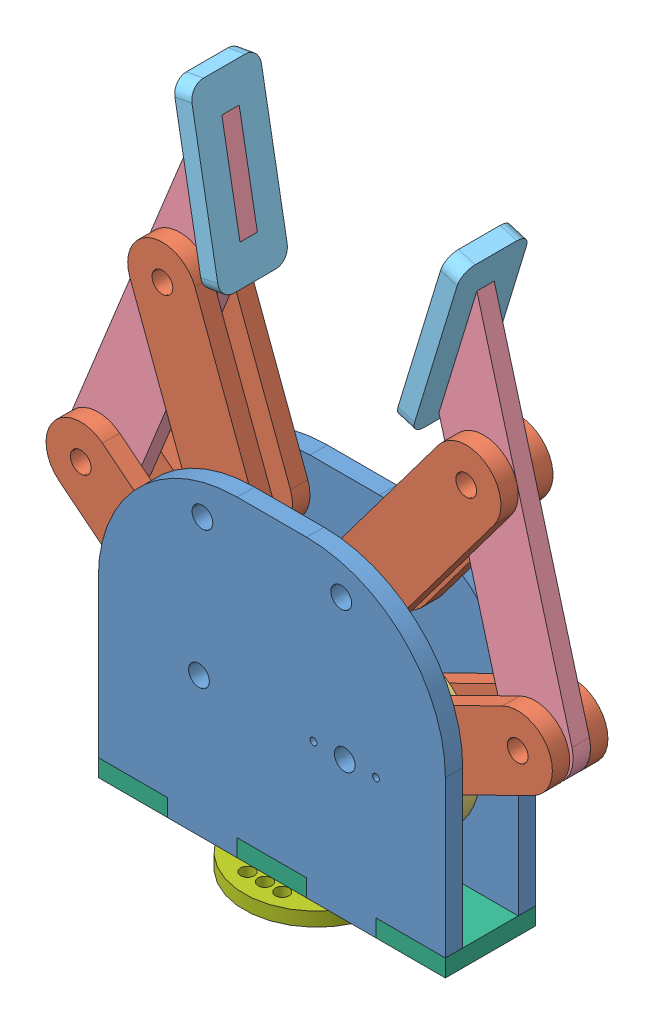
SolidWorks assembly BT_Ensamblaje_PINZA, configuration Predeterminado. Lengths in mm.
Overall size (76.67 96.09 21).
18 component instances, 7 part files, 45 mates.
Components (placement in the parent):
- BT_Base_Pinza-1: BT_Base_Pinza [Predeterminado] at origin size (50 45 2.5)
- BT_Esla_peque-1: BT_Esla_peque [Predeterminado] at (-10.5 -10 8) x (0.62437 0.781129 0) z (0 0 1) size (10 35 2.5)
- BT_Engrane-1: BT_Engrane [Predeterminado] at (-10.5 -10 5) size (23 23 3)
- BT_Engrane-2: BT_Engrane [Predeterminado] at (10.5 -10 5) size (23 23 3)
- BT_Esla_peque-2: BT_Esla_peque [Predeterminado] at (10.5 -10 8) x (0.442571 -0.896734 0) z (0 0 1) size (10 35 2.5)
- BT_Esla_peque-3: BT_Esla_peque [Predeterminado] at (-10.5 -10 2.5) x (0.62437 0.781129 0) z (0 0 1) size (10 35 2.5)
- BT_Esla_peque-4: BT_Esla_peque [Predeterminado] at (10.5 -10 2.5) x (0.442571 -0.896734 0) z (0 0 1) size (10 35 2.5)
- BT_Esla_peque-5: BT_Esla_peque [Predeterminado] at (-10 10 2.5) x (0.936554 0.350522 0) z (0 0 1) size (10 35 2.5)
- BT_Esla_peque-6: BT_Esla_peque [Predeterminado] at (10 10 7.5) x (0.800012 -0.599984 0) z (0 0 1) size (10 35 2.5)
- BT_Esla_peque-7: BT_Esla_peque [Predeterminado] at (-10 10 7.5) x (0.936554 0.350522 0) z (0 0 1) size (10 35 2.5)
- BT_Esla_peque-8: BT_Esla_peque [Predeterminado] at (10 10 2.5) x (0.800012 -0.599984 0) z (0 0 1) size (10 35 2.5)
- BT_Elsa_Grande-1: BT_Elsa_Grande [Predeterminado] at (-30.0282 5.6093 7.5) x (-0.92682 0.375505 0) z (0 0 -1) size (10 58.26 2.5)
- BT_Elsa_Grande-2: BT_Elsa_Grande [Predeterminado] at (32.9183 1.0643 5) x (0.964534 0.263958 0) z (0 0 1) size (10 58.26 2.5)
- BT_Llema-1: BT_Llema [Predeterminado] at (19.489 46.132 6.25) x (0 0 -1) z (0.956576 -0.291484 0) size (10 25 2.5)
- BT_Llema-2: BT_Llema [Predeterminado] at (-11.3944 48.7859 6.25) x (0 0 1) z (-0.984207 -0.177021 0) size (10 25 2.5)
- BT_Base_Pinza-2: BT_Base_Pinza [Predeterminado] at (0 0 10.5) size (50 45 2.5)
- BT_Tapa-1: BT_Tapa [Predeterminado] at (0 -30 6.5) x (1 0 0) z (0 1 0) size (50 13 2.5)
- BT_acople_servos-1: BT_acople_servos [Default] at (0 -31 6.5) x (1 0 0) z (0 -1 0) size (21 21 5.5)
Mates (geometry in assembly coordinates):
- Coincidente1: coincident anti-aligned: plane of BT_Esla_peque-1 through (-30.0282 5.6093 8) normal (0 0 -1); plane of BT_Engrane-1 through (-10.5 -10 8) normal (0 0 1)
- Concéntrica1: concentric aligned: cylinder of BT_Esla_peque-1 through (-10.5 -10 10.5) axis (0 0 -1) radius 1.5; cylinder of BT_Engrane-1 through (-10.5 -10 8) axis (0 0 -1) radius 1.5
- Concéntrica2: concentric aligned: cylinder of BT_Engrane-1 through (-10.5 -10 8) axis (0 0 -1) radius 1.5; cylinder of BT_Esla_peque-3 through (-10.5 -10 5) axis (0 0 -1) radius 1.5
- Coincidente2: coincident anti-aligned: plane of BT_Engrane-1 through (-10.5 -10 5) normal (0 0 -1); plane of BT_Esla_peque-3 through (-30.0282 5.6093 5) normal (0 0 1)
- Concéntrica3: concentric aligned: cylinder of BT_Esla_peque-1 through (-30.0282 5.6093 10.5) axis (0 0 -1) radius 5; cylinder of BT_Esla_peque-3 through (-30.0282 5.6093 5) axis (0 0 -1) radius 5
- Coincidente3: coincident anti-aligned: plane of BT_Engrane-2 through (10.5 -10 8) normal (0 0 1); plane of BT_Esla_peque-2 through (32.9183 1.0643 8) normal (0 0 -1)
- Concéntrica4: concentric aligned: cylinder of BT_Engrane-2 through (10.5 -10 8) axis (0 0 -1) radius 1.5; cylinder of BT_Esla_peque-2 through (10.5 -10 10.5) axis (0 0 -1) radius 1.5
- Coincidente4: coincident anti-aligned: plane of BT_Engrane-2 through (10.5 -10 5) normal (0 0 -1); plane of BT_Esla_peque-4 through (32.9183 1.0643 5) normal (0 0 1)
- Concéntrica5: concentric aligned: cylinder of BT_Engrane-2 through (10.5 -10 8) axis (0 0 -1) radius 1.5; cylinder of BT_Esla_peque-4 through (10.5 -10 5) axis (0 0 -1) radius 1.5
- Concéntrica6: concentric aligned: cylinder of BT_Esla_peque-2 through (32.9183 1.0643 10.5) axis (0 0 -1) radius 5; cylinder of BT_Esla_peque-4 through (32.9183 1.0643 5) axis (0 0 -1) radius 5
- Concéntrica7: concentric aligned: cylinder of BT_Base_Pinza-1 through (10.5 -10 2.5) axis (0 0 -1) radius 1.5; cylinder of BT_Esla_peque-2 through (10.5 -10 10.5) axis (0 0 -1) radius 1.5
- Coincidente5: coincident anti-aligned: plane of BT_Base_Pinza-1 through (5 -5 2.5) normal (0 0 1); plane of BT_Esla_peque-4 through (32.9183 1.0643 2.5) normal (0 0 -1)
- Coincidente6: coincident anti-aligned: plane of BT_Base_Pinza-1 through (5 -5 2.5) normal (0 0 1); plane of BT_Esla_peque-3 through (-30.0282 5.6093 2.5) normal (0 0 -1)
- Concéntrica8: concentric aligned: cylinder of BT_Base_Pinza-1 through (-10.5 -10 2.5) axis (0 0 -1) radius 1.5; cylinder of BT_Esla_peque-1 through (-10.5 -10 10.5) axis (0 0 -1) radius 1.5
- Coincidente7: coincident anti-aligned: circle of BT_Base_Pinza-1; cylinder of BT_Esla_peque-8 through (10 10 5) axis (0 0 -1) radius 1.5
- Concéntrica9: concentric aligned: cylinder of BT_Base_Pinza-1 through (-10 10 2.5) axis (0 0 -1) radius 1.5; cylinder of BT_Esla_peque-5 through (-10 10 5) axis (0 0 -1) radius 1.5
- Coincidente8: coincident anti-aligned: plane of BT_Base_Pinza-1 through (5 -5 2.5) normal (0 0 1); plane of BT_Esla_peque-8 through (24.9996 30.0003 2.5) normal (0 0 -1)
- Coincidente9: coincident anti-aligned: plane of BT_Base_Pinza-1 through (5 -5 2.5) normal (0 0 1); plane of BT_Esla_peque-5 through (-18.7631 33.4139 2.5) normal (0 0 -1)
- Coincidente10: coincident anti-aligned: plane of BT_Esla_peque-3 through (-30.0282 5.6093 5) normal (0 0 1); plane of BT_Elsa_Grande-1 through (-30.0282 5.6093 5) normal (0 0 -1)
- Concéntrica10: concentric anti-aligned: cylinder of BT_Esla_peque-3 through (-30.0282 5.6093 5) axis (0 0 -1) radius 1.5; cylinder of BT_Elsa_Grande-1 through (-30.0282 5.6093 5) axis (0 0 1) radius 1.5
- Concéntrica11: concentric anti-aligned: cylinder of BT_Esla_peque-5 through (-18.7631 33.4139 5) axis (0 0 -1) radius 1.5; cylinder of BT_Elsa_Grande-1 through (-18.7631 33.4139 5) axis (0 0 1) radius 1.5
- Coincidente11: coincident anti-aligned: plane of BT_Esla_peque-4 through (32.9183 1.0643 5) normal (0 0 1); plane of BT_Elsa_Grande-2 through (32.9183 1.0643 5) normal (0 0 -1)
- Concéntrica12: concentric aligned: cylinder of BT_Esla_peque-4 through (32.9183 1.0643 5) axis (0 0 -1) radius 1.5; cylinder of BT_Elsa_Grande-2 through (32.9183 1.0643 7.5) axis (0 0 -1) radius 1.5
- Concéntrica13: concentric aligned: cylinder of BT_Esla_peque-8 through (24.9996 30.0003 5) axis (0 0 -1) radius 1.5; cylinder of BT_Elsa_Grande-2 through (24.9996 30.0003 7.5) axis (0 0 -1) radius 1.5
- Coincidente12: coincident anti-aligned: plane of BT_Elsa_Grande-2 through (19.7267 38.3355 7.5) normal (-0.956576 0.291484 0); plane of BT_Llema-1 through (21.8804 45.4032 6.25) normal (0.956576 -0.291484 0)
- Coincidente13: coincident anti-aligned: plane of BT_Elsa_Grande-2 through (32.9183 1.0643 5) normal (0 0 -1); plane of BT_Llema-1 through (24.0341 52.471 5) normal (0 0 1)
- Coincidente14: coincident anti-aligned: plane of BT_Elsa_Grande-2 through (17.3353 39.0642 7.5) normal (-0.291484 -0.956576 0); plane of BT_Llema-1 through (19.7267 38.3355 7.5) normal (0.291484 0.956576 0)
- Coincidente15: coincident anti-aligned: plane of BT_Elsa_Grande-1 through (-12.547 41.0715 5) normal (0.984207 0.177021 0); plane of BT_Llema-2 through (-13.8549 48.3434 6.25) normal (-0.984207 -0.177021 0)
- Coincidente16: coincident anti-aligned: plane of BT_Elsa_Grande-1 through (-10.0864 41.514 5) normal (0.177021 -0.984207 0); plane of BT_Llema-2 through (-12.547 41.0715 5) normal (-0.177021 0.984207 0)
- Coincidente17: coincident anti-aligned: plane of BT_Elsa_Grande-1 through (-30.0282 5.6093 7.5) normal (0 0 1); plane of BT_Llema-2 through (-15.1628 55.6153 7.5) normal (0 0 -1)
- Concéntrica14: concentric aligned: cylinder of BT_Esla_peque-5 through (-10 10 5) axis (0 0 -1) radius 1.5; cylinder of BT_Esla_peque-7 through (-10 10 10) axis (0 0 -1) radius 1.5
- Coincidente18: coincident anti-aligned: plane of BT_Esla_peque-7 through (-18.7631 33.4139 7.5) normal (0 0 -1); plane of BT_Elsa_Grande-1 through (-30.0282 5.6093 7.5) normal (0 0 1)
- Concéntrica15: concentric anti-aligned: cylinder of BT_Esla_peque-7 through (-18.7631 33.4139 10) axis (0 0 -1) radius 1.5; cylinder of BT_Elsa_Grande-1 through (-18.7631 33.4139 5) axis (0 0 1) radius 1.5
- Coincidente19: coincident anti-aligned: plane of BT_Esla_peque-6 through (24.9996 30.0003 7.5) normal (0 0 -1); plane of BT_Elsa_Grande-2 through (32.9183 1.0643 7.5) normal (0 0 1)
- Concéntrica16: concentric aligned: cylinder of BT_Esla_peque-6 through (10 10 10) axis (0 0 -1) radius 1.5; cylinder of BT_Esla_peque-8 through (10 10 5) axis (0 0 -1) radius 1.5
- Concéntrica17: concentric aligned: cylinder of BT_Esla_peque-6 through (24.9996 30.0003 10) axis (0 0 -1) radius 1.5; cylinder of BT_Elsa_Grande-2 through (24.9996 30.0003 7.5) axis (0 0 -1) radius 1.5
- Coincidente20: coincident anti-aligned: plane of BT_Esla_peque-2 through (32.9183 1.0643 10.5) normal (0 0 1); plane of BT_Base_Pinza-2 through (5 -5 10.5) normal (0 0 -1)
- Coincidente22: coincident aligned: plane of BT_Base_Pinza-1 through (25 -15 2.5) normal (1 0 0); plane of BT_Base_Pinza-2 through (25 -15 13) normal (1 0 0)
- Coincidente23: coincident aligned: plane of BT_Base_Pinza-1 through (-5 -27.5 2.5) normal (0 -1 0); plane of BT_Base_Pinza-2 through (-5 -27.5 13) normal (0 -1 0)
- Coincidente24: coincident anti-aligned: plane of BT_Base_Pinza-2 through (-25 -27.5 13) normal (0 -1 0); plane of BT_Tapa-1 through (0 -27.5 6.5) normal (0 1 0)
- Coincidente25: coincident anti-aligned: plane of BT_Base_Pinza-2 through (5 -5 10.5) normal (0 0 -1); plane of BT_Tapa-1 through (-15 -27.5 10.5) normal (0 0 1)
- Coincidente26: coincident anti-aligned: plane of BT_Base_Pinza-2 through (-15 -27.5 13) normal (-1 0 0); plane of BT_Tapa-1 through (-15 -27.5 13) normal (1 0 0)
- Coincidente27: coincident: plane of BT_Tapa-1 through (0 -30 6.5) normal (0 -1 0); plane of BT_acople_servos-1 through (0 -30 11) normal (0 1 0)
- Concéntrica18: concentric: cylinder of BT_Tapa-1 through (0 -27.5 6.5) axis (0 -1 0) radius 1.5; cylinder of BT_acople_servos-1 through (0 -31 6.5) axis (0 1 0) radius 1.5
- Concéntrica19: concentric anti-aligned: cylinder of BT_Tapa-1 through (7.5 -27.5 6.5) axis (0 -1 0) radius 0.9778; cylinder of BT_acople_servos-1 through (7.5 -33 6.5) axis (0 1 0) radius 1
